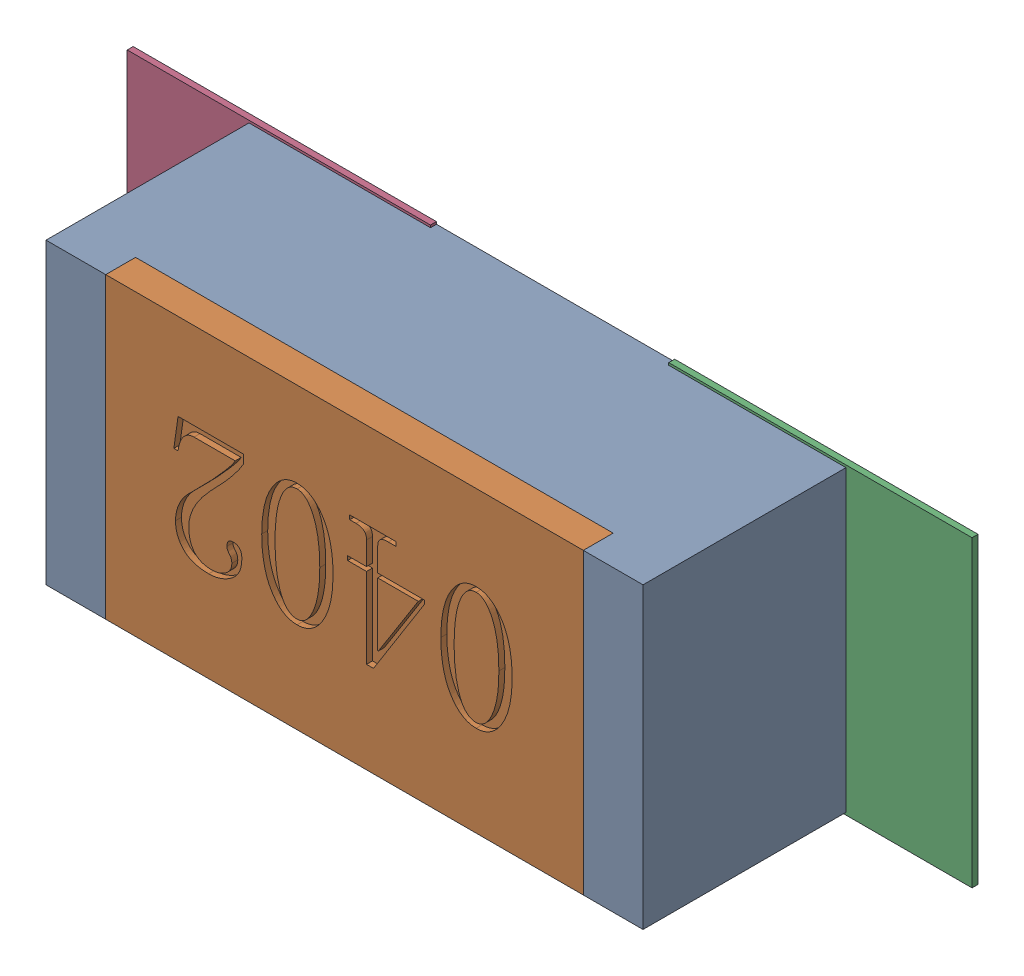
SolidWorks assembly R91, configuration Défaut. Lengths in mm.
Overall size (1.42 0.51 0.35).
5 component instances, 2 part files, 0 mates.
Components (placement in the parent):
- R0402-1: R0402 [Défaut] at (45.8724 -25.4761 0) x (-1 0 0) z (0 0 1) size (1 0.5 0.35)
- 6504207776-1: 6504207776 [Défaut] at (46.3295 -25.4762 0) size (0.51 0.51 0.01)
  - Extruded-1: Extruded [Défaut] at origin size (0.51 0.51 0.01)
- 6504207776-2: 6504207776 [Défaut] at (45.4224 -25.4762 0) size (0.51 0.51 0.01)
  - Extruded-1: Extruded [Défaut] at origin size (0.51 0.51 0.01)
